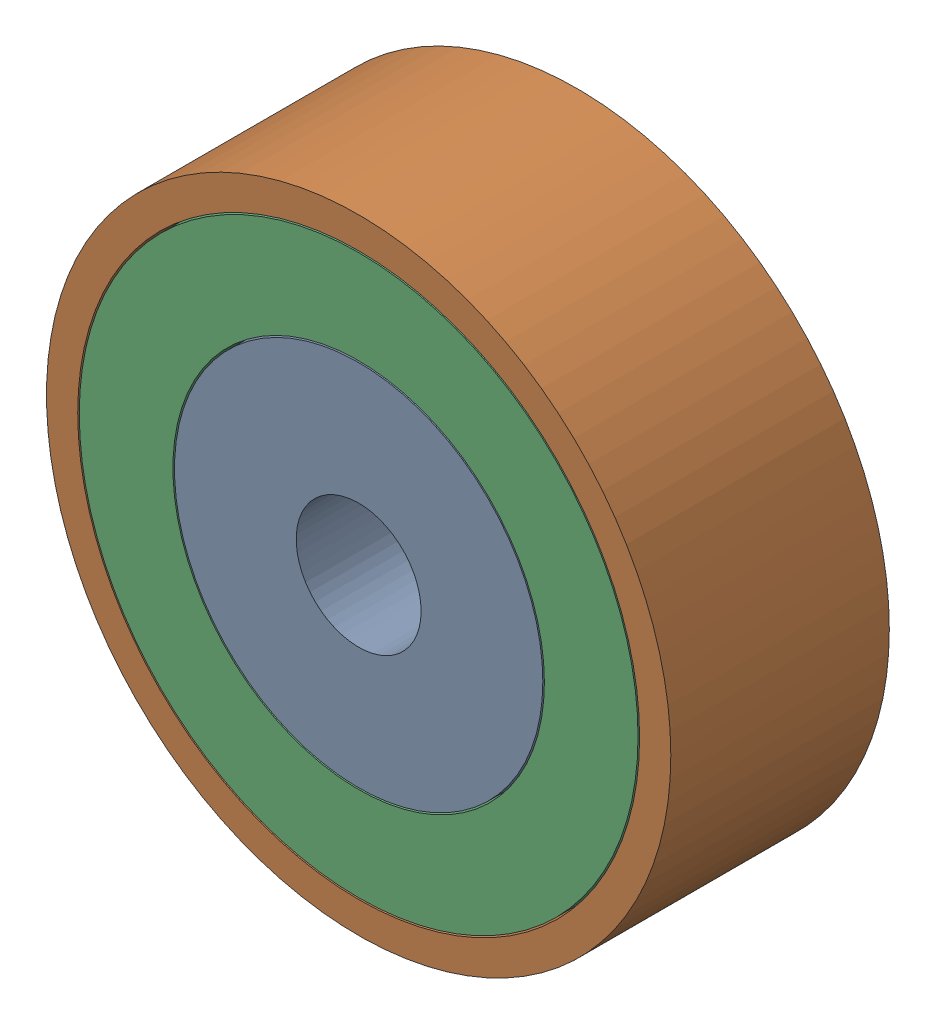
SolidWorks assembly 镜向轴承2, configuration 默认. Lengths in mm.
Overall size (20 20 7).
3 component instances, 3 part files, 4 mates.
Components (placement in the parent):
- 镜向轴承内圈-1: 镜向轴承内圈 [默认] at (-5.0655 0.8032 -6.5) size (11.8 11.8 7)
- 镜向轴承外圈-1: 镜向轴承外圈 [默认] at (-5.0655 0.8032 -6.5) size (20 20 7)
- 镜向轴承中圈-1: 镜向轴承中圈 [默认] at (-5.0655 0.8032 -6.5) size (17.9 17.9 7)
Mates (geometry in assembly coordinates):
- 重合1: coincident: plane of ? through (-5.0655 0.8032 -13.5) normal (0 0 -1); plane of ? through (-5.0655 0.8032 -13.5) normal (0 0 -1)
- 重合2: coincident: plane of ? through (-5.0655 0.8032 -13.5) normal (0 0 -1); plane of ? through (-5.0655 0.8032 -13.5) normal (0 0 -1)
- 同心1: concentric: cylinder of ? through (-5.0655 0.8032 -13.5) axis (0 0 1) radius 9; cylinder of ? through (-5.0655 0.8032 -13.5) axis (0 0 1) radius 8.95
- 同心2: concentric: cylinder of ? through (-5.0655 0.8032 -13.5) axis (0 0 1) radius 5.9; cylinder of ? through (-5.0655 0.8032 -13.5) axis (0 0 1) radius 5.95
